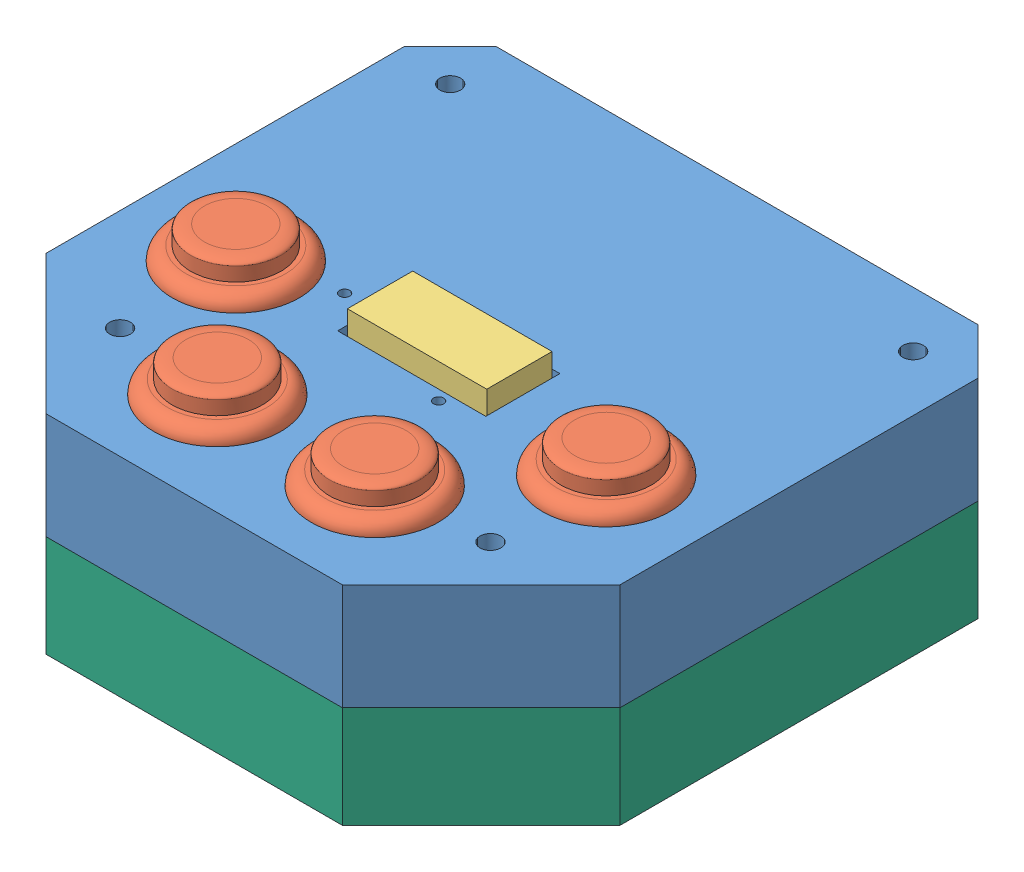
SolidWorks assembly boxing, configuration Défaut. Lengths in mm.
Overall size (124 52.01 117.31).
9 component instances, 6 part files, 20 mates.
Components (placement in the parent):
- boxing-top-1: boxing-top [Défaut] at origin size (124 38 117.31)
- ArcadeButton^boxing-1: ArcadeButton^boxing [Défaut] at (-40 -24.8 -27) size (32.2 34.8 32.2) (virtual)
- GrouveDisplay^boxing-1: GrouveDisplay^boxing [Défaut] at (-22.279 -1.7 -22.7832) size (42.35 13.9 24.1) (virtual)
- GrouveRelay^boxing-1: GrouveRelay^boxing [Défaut] at (-15.9049 -35 -74.3798) x (-1 0 0) z (0 0 -1) size (42.35 17 24.1) (virtual)
- Timer^boxing-1: Timer^boxing [Défaut] at (-8 -35 -40.31) size (52 16.9 51.6) (virtual)
- ArcadeButton^boxing-2: ArcadeButton^boxing [Défaut] at (17 -24.8 0) size (32.2 34.8 32.2) (virtual)
- ArcadeButton^boxing-3: ArcadeButton^boxing [Défaut] at (40 -24.8 -27) size (32.2 34.8 32.2) (virtual)
- ArcadeButton^boxing-4: ArcadeButton^boxing [Défaut] at (-17 -24.8 0) size (32.2 34.8 32.2) (virtual)
- boxing-bottom-1: boxing-bottom [Défaut] at (-62 -42 22) size (124 30.75 117.31)
Mates (geometry in assembly coordinates):
- Coïncidente1: coincident anti-aligned: plane of boxing-top-1 through (0 0 0) normal (0 -1 0); plane of GrouveDisplay^boxing-1 through (-22.279 0 -22.7832) normal (0 1 0)
- Coaxiale1: concentric aligned: circle of boxing-top-1; circle of ArcadeButton^boxing-4
- Coaxiale2: concentric aligned: circle of boxing-top-1; circle of ArcadeButton^boxing-1
- Coaxiale3: concentric aligned: circle of boxing-top-1; circle of ArcadeButton^boxing-2
- Coaxiale4: concentric aligned: circle of boxing-top-1; circle of ArcadeButton^boxing-3
- Coïncidente8: coincident anti-aligned: plane of boxing-top-1 through (0 3 0) normal (0 1 0); plane of ArcadeButton^boxing-2 through (17 3 0) normal (0 -1 0)
- Coïncidente9: coincident anti-aligned: plane of boxing-top-1 through (0 3 0) normal (0 1 0); plane of ArcadeButton^boxing-3 through (40 3 -27) normal (0 -1 0)
- Coïncidente10: coincident anti-aligned: plane of boxing-top-1 through (0 3 0) normal (0 1 0); plane of ArcadeButton^boxing-4 through (-17 3 0) normal (0 -1 0)
- Coïncidente11: coincident anti-aligned: plane of boxing-top-1 through (0 3 0) normal (0 1 0); plane of ArcadeButton^boxing-1 through (-40 3 -27) normal (0 -1 0)
- Coïncidente12: coincident aligned: plane of boxing-top-1 through (62 3 22) normal (0 0 1); plane of boxing-bottom-1 through (-62 -35 22) normal (0 0 1)
- Coïncidente13: coincident aligned: plane of boxing-top-1 through (62 3 22) normal (1 0 0); plane of boxing-bottom-1 through (62 -35 22) normal (1 0 0)
- Coïncidente14: coincident anti-aligned: plane of boxing-top-1 through (0 -20 0) normal (0 -1 0); plane of boxing-bottom-1 through (-62 -20 22) normal (0 1 0)
- Coïncidente15: coincident anti-aligned: plane of Timer^boxing-1 through (-8 -35 -40.31) normal (0 -1 0); plane of boxing-bottom-1 through (-62 -35 22) normal (0 1 0)
- Coïncidente17: coincident anti-aligned: plane of GrouveRelay^boxing-1 through (-15.9049 -35 -74.3798) normal (0 -1 0); plane of boxing-bottom-1 through (-62 -35 22) normal (0 1 0)
- Parallèle1: parallel anti-aligned: plane of GrouveRelay^boxing-1 through (-15.9049 -18 -72.0048) normal (0 0 -1); plane of boxing-bottom-1 through (-62 -15 -91.31) normal (0 0 1)
- Coaxiale5: concentric aligned: circle of boxing-top-1; circle of GrouveDisplay^boxing-1
- Coaxiale6: concentric aligned: circle of boxing-top-1; circle of GrouveDisplay^boxing-1
- Coaxiale7: concentric anti-aligned: circle of Timer^boxing-1; circle of boxing-bottom-1
- Coaxiale8: concentric anti-aligned: circle of Timer^boxing-1; circle of boxing-bottom-1
- Coaxiale9: concentric anti-aligned: circle of GrouveRelay^boxing-1; circle of boxing-bottom-1
